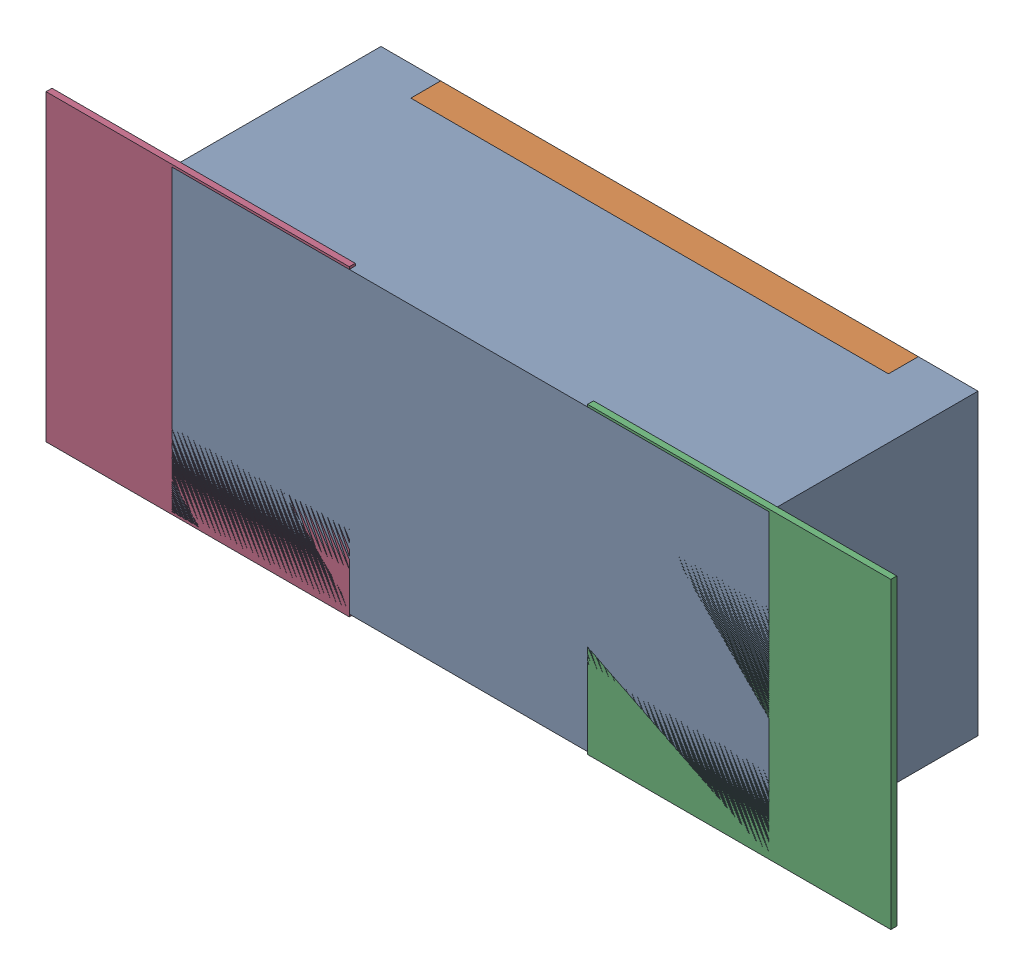
SolidWorks assembly R33, configuration Défaut. Lengths in mm.
Overall size (1.42 0.51 0.35).
5 component instances, 2 part files, 0 mates.
Components (placement in the parent):
- R0402-1: R0402 [Défaut] at (24.5364 -27.1525 -2.0818) x (1 0 0) z (0 0 -1) size (1 0.5 0.35)
- 6504207776-1: 6504207776 [Défaut] at (24.9864 -27.1526 -2.0918) size (0.51 0.51 0.01)
  - Extruded-1: Extruded [Défaut] at origin size (0.51 0.51 0.01)
- 6504207776-2: 6504207776 [Défaut] at (24.0793 -27.1526 -2.0918) size (0.51 0.51 0.01)
  - Extruded-1: Extruded [Défaut] at origin size (0.51 0.51 0.01)
